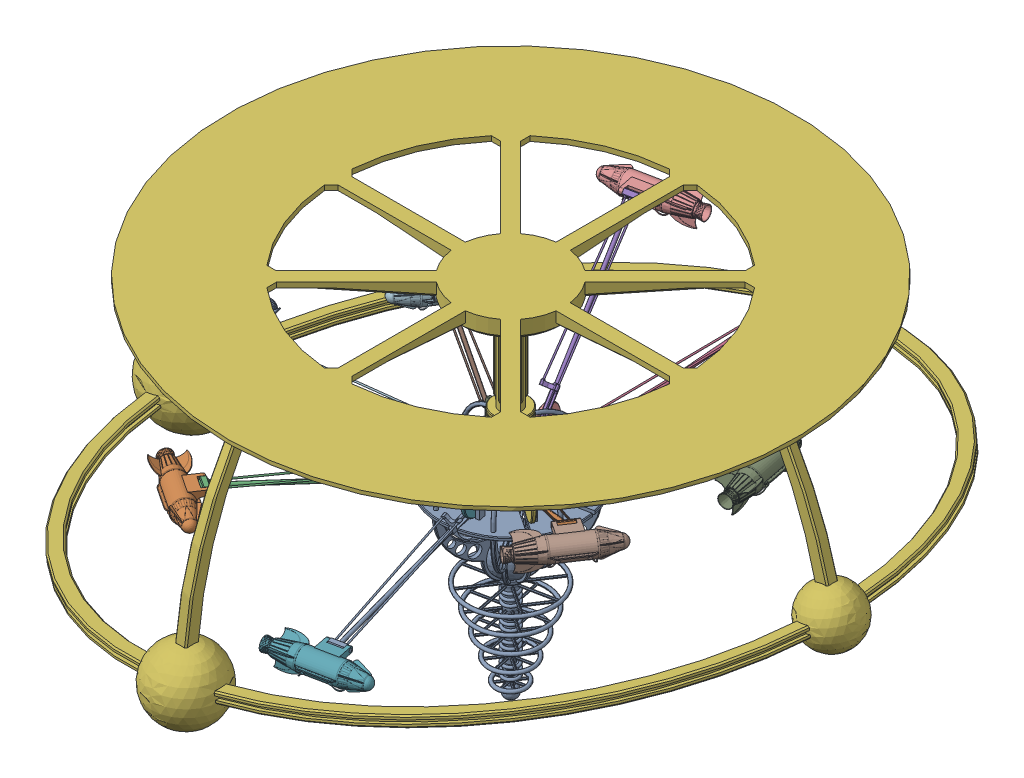
SolidWorks assembly Astro Orbiter Assembly, configuration Default. Lengths in mm.
Overall size (1005.89 517.61 1020).
26 component instances, 5 part files, 74 mates.
Components (placement in the parent):
- Astro Orbiter 1-1: Astro Orbiter 1 [Default] at (-37.4534 8.2623 -30.7627) x (-0.832861 0 -0.553482) z (0.553482 0 -0.832861) size (199.94 344.61 199.94)
- Astro Orbiter 2-1: Astro Orbiter 2 [Default] at (-69.9507 38.7623 31.6887) x (0.48296 0.488461 -0.726743) z (-0.832861 0 -0.553482) size (50 50 10)
- Astro Orbiter 3-1: Astro Orbiter 3 [Default] at (-76.7931 26.9845 23.9175) x (-0.550749 0.099257 0.828749) z (0.832861 0 0.553482) size (293 20 30)
- Astro Orbiter 2-2: Astro Orbiter 2 [Default] at (-4.9562 38.7623 -93.2141) x (-0.258225 -0.884497 0.388568) z (0.832861 0 0.553482) size (50 50 10)
- Astro Orbiter 2-3: Astro Orbiter 2 [Default] at (29.6854 38.7623 -51.9435) x (0.956571 0.218659 -0.192771) z (0.197551 0 0.980293) size (50 50 10)
- Astro Orbiter 2-4: Astro Orbiter 2 [Default] at (24.998 38.7623 1.7345) x (-0.624057 -0.662239 -0.41472) z (-0.553482 0 0.832861) size (50 50 10)
- Astro Orbiter 2-5: Astro Orbiter 2 [Default] at (-16.2727 38.7623 36.3761) x (0.064285 0.945574 0.318995) z (-0.980293 0 0.197551) size (50 50 10)
- Astro Orbiter 2-6: Astro Orbiter 2 [Default] at (-104.5923 38.7623 -9.5819) x (-0.782619 0.60219 0.157716) z (-0.197551 0 -0.980293) size (50 50 10)
- Astro Orbiter 2-7: Astro Orbiter 2 [Default] at (-99.9048 38.7623 -63.26) x (-0.518205 0.78286 -0.344375) z (0.553482 0 -0.832861) size (50 50 10)
- Astro Orbiter 2-8: Astro Orbiter 2 [Default] at (-58.6342 38.7623 -97.9016) x (-0.178151 -0.432156 -0.884027) z (0.980293 0 -0.197551) size (50 50 10)
- Astro Orbiter 3-2: Astro Orbiter 3 [Default] at (-92.2874 23.0484 -70.2045) x (-0.832848 -0.005705 -0.553473) z (-0.553482 0 0.832861) size (293 20 30)
- Astro Orbiter 3-3: Astro Orbiter 3 [Default] at (-103.7427 28.6003 -19.9542) x (-0.97031 0.142346 0.19554) z (0.197551 0 0.980293) size (293 20 30)
- Astro Orbiter 3-4: Astro Orbiter 3 [Default] at (-26.6076 19.4622 35.7117) x (0.196534 -0.101336 0.975246) z (0.980293 0 -0.197551) size (293 20 30)
- Astro Orbiter 3-5: Astro Orbiter 3 [Default] at (13.8271 40.6354 6.3177) x (0.738091 0.463282 0.490502) z (0.553482 0 -0.832861) size (293 20 30)
- Astro Orbiter 3-6: Astro Orbiter 3 [Default] at (24.7521 41.1619 -40.7483) x (0.861411 0.477322 -0.173594) z (-0.197551 0 -0.980293) size (293 20 30)
- Astro Orbiter 3-7: Astro Orbiter 3 [Default] at (-1.5461 44.1955 -80.2781) x (0.45922 0.558219 -0.69102) z (-0.832861 0 -0.553482) size (293 20 30)
- Astro Orbiter 3-8: Astro Orbiter 3 [Default] at (-45.9145 51.0011 -85.4032) x (-0.132939 0.7397 -0.659675) z (-0.980293 0 0.197551) size (293 20 30)
- Astro Orbiter 4-1: Astro Orbiter 4 [Default] at (-37.4534 3.2623 -30.7627) size (1005.89 407.25 1020)
- Astro Orbiter 5-1: Astro Orbiter 5 [Default] at (87.9556 -15.517 289.3084) x (-0.980293 0 0.197551) z (0.197551 0 0.980293) size (131 41.05 52.64)
- Astro Orbiter 5-2: Astro Orbiter 5 [Default] at (251.8514 144.8343 89.807) x (-0.553482 0 0.832861) z (0.832861 0 0.553482) size (131 41.05 52.64)
- Astro Orbiter 5-3: Astro Orbiter 5 [Default] at (250.2885 148.8217 -149.6567) x (0.197551 0 0.980293) z (0.980293 0 -0.197551) size (131 41.05 52.64)
- Astro Orbiter 5-4: Astro Orbiter 5 [Default] at (-144.8016 223.3372 -261.2115) x (0.980293 0 -0.197551) z (-0.197551 0 -0.980293) size (131 41.05 52.64)
- Astro Orbiter 5-5: Astro Orbiter 5 [Default] at (74.2323 171.7966 -306.6993) x (0.832861 0 0.553482) z (0.553482 0 -0.832861) size (131 41.05 52.64)
- Astro Orbiter 5-6: Astro Orbiter 5 [Default] at (-353.6693 11.6422 -169.2162) x (0.553482 0 -0.832861) z (-0.832861 0 -0.553482) size (131 41.05 52.64)
- Astro Orbiter 5-7: Astro Orbiter 5 [Default] at (-356.1227 53.6886 94.3639) x (-0.197551 0 -0.980293) z (-0.980293 0 0.197551) size (131 41.05 52.64)
- Astro Orbiter 5-8: Astro Orbiter 5 [Default] at (-175.1332 41.4513 284.2889) x (-0.832861 0 -0.553482) z (-0.553482 0 0.832861) size (131 41.05 52.64)
Mates (geometry in assembly coordinates):
- Coincident1: coincident anti-aligned: plane of Astro Orbiter 1-1 through (-67.1833 43.2623 27.5244) normal (-0.832861 0 -0.553482); plane of Astro Orbiter 2-1 through (-69.9507 38.7623 31.6887) normal (0.832861 0 0.553482)
- Concentric1: concentric anti-aligned: cylinder of Astro Orbiter 1-1 through (-74.115 38.7623 28.9213) axis (0.832861 0 0.553482) radius 2.5; circle of Astro Orbiter 2-1
- Concentric2: concentric anti-aligned: cylinder of Astro Orbiter 1-1 through (-47.8114 23.2623 -1.6258) axis (-0.832861 0 -0.553482) radius 2.5; cylinder of Astro Orbiter 3-1 through (-60.3043 23.2623 -9.928) axis (0.832861 0 0.553482) radius 2.5
- Coincident3: coincident anti-aligned: plane of Astro Orbiter 1-1 through (-39.5356 28.2623 -32.1464) normal (0.832861 0 0.553482); plane of Astro Orbiter 3-1 through (-76.7931 26.9845 23.9175) normal (-0.832861 0 -0.553482)
- Tangent1: tangent anti-aligned: cylinder of Astro Orbiter 2-1 through (-87.9385 28.9931 40.6887) axis (0.832861 0 0.553482) radius 2.5; plane of Astro Orbiter 3-1 through (-61.7849 21.7672 1.3336) normal (0.054937 0.995062 -0.082667)
- Concentric3: concentric aligned: cylinder of Astro Orbiter 1-1 through (-0.7919 38.7623 -90.4467) axis (-0.832861 0 -0.553482) radius 2.5; cylinder of Astro Orbiter 2-2 through (-0.7919 38.7623 -90.4467) axis (-0.832861 0 -0.553482) radius 2.5
- Coincident4: coincident anti-aligned: plane of Astro Orbiter 1-1 through (-7.7236 43.2623 -89.0498) normal (0.832861 0 0.553482); plane of Astro Orbiter 2-2 through (-4.9562 38.7623 -93.2141) normal (-0.832861 0 -0.553482)
- Concentric4: concentric aligned: cylinder of Astro Orbiter 1-1 through (30.6732 38.7623 -47.042) axis (-0.197551 0 -0.980293) radius 2.5; cylinder of Astro Orbiter 2-3 through (30.6732 38.7623 -47.042) axis (-0.197551 0 -0.980293) radius 2.5
- Coincident5: coincident anti-aligned: plane of Astro Orbiter 1-1 through (24.7839 43.2623 -50.9557) normal (0.197551 0 0.980293); plane of Astro Orbiter 2-3 through (29.6854 38.7623 -51.9435) normal (-0.197551 0 -0.980293)
- Concentric5: concentric aligned: cylinder of Astro Orbiter 1-1 through (22.2306 38.7623 5.8988) axis (0.553482 0 -0.832861) radius 2.5; cylinder of Astro Orbiter 2-4 through (22.2306 38.7623 5.8988) axis (0.553482 0 -0.832861) radius 2.5
- Coincident6: coincident anti-aligned: plane of Astro Orbiter 1-1 through (20.8337 43.2623 -1.0329) normal (-0.553482 0 0.832861); plane of Astro Orbiter 2-4 through (24.998 38.7623 1.7345) normal (0.553482 0 -0.832861)
- Concentric6: concentric aligned: cylinder of Astro Orbiter 1-1 through (-21.1741 38.7623 37.3639) axis (0.980293 0 -0.197551) radius 2.5; cylinder of Astro Orbiter 2-5 through (-21.1741 38.7623 37.3639) axis (0.980293 0 -0.197551) radius 2.5
- Coincident7: coincident anti-aligned: plane of Astro Orbiter 1-1 through (-17.2604 43.2623 31.4747) normal (-0.980293 0 0.197551); plane of Astro Orbiter 2-5 through (-16.2727 38.7623 36.3761) normal (0.980293 0 -0.197551)
- Concentric7: concentric aligned: cylinder of Astro Orbiter 1-1 through (-105.58 38.7623 -14.4834) axis (0.197551 0 0.980293) radius 2.5; cylinder of Astro Orbiter 2-6 through (-105.58 38.7623 -14.4834) axis (0.197551 0 0.980293) radius 2.5
- Coincident8: coincident anti-aligned: plane of Astro Orbiter 1-1 through (-99.6908 43.2623 -10.5697) normal (-0.197551 0 -0.980293); plane of Astro Orbiter 2-6 through (-104.5923 38.7623 -9.5819) normal (0.197551 0 0.980293)
- Concentric8: concentric aligned: cylinder of Astro Orbiter 1-1 through (-97.1374 38.7623 -67.4243) axis (-0.553482 0 0.832861) radius 2.5; cylinder of Astro Orbiter 2-7 through (-97.1374 38.7623 -67.4243) axis (-0.553482 0 0.832861) radius 2.5
- Coincident9: coincident anti-aligned: plane of Astro Orbiter 1-1 through (-95.7405 43.2623 -60.4926) normal (0.553482 0 -0.832861); plane of Astro Orbiter 2-7 through (-99.9048 38.7623 -63.26) normal (-0.553482 0 0.832861)
- Concentric9: concentric aligned: cylinder of Astro Orbiter 1-1 through (-53.7328 38.7623 -98.8893) axis (-0.980293 0 0.197551) radius 2.5; cylinder of Astro Orbiter 2-8 through (-53.7328 38.7623 -98.8893) axis (-0.980293 0 0.197551) radius 2.5
- Coincident10: coincident anti-aligned: plane of Astro Orbiter 1-1 through (-57.6465 43.2623 -93.0001) normal (0.980293 0 -0.197551); plane of Astro Orbiter 2-8 through (-58.6342 38.7623 -97.9016) normal (-0.980293 0 0.197551)
- Concentric12: concentric anti-aligned: cylinder of Astro Orbiter 1-1 through (-24.1747 23.2623 -2.8356) axis (-0.980293 0 0.197551) radius 2.5; cylinder of Astro Orbiter 3-4 through (-38.8791 23.2623 0.1277) axis (0.980293 0 -0.197551) radius 2.5
- Coincident13: coincident anti-aligned: plane of Astro Orbiter 1-1 through (-39.9042 28.2623 -30.2688) normal (0.980293 0 -0.197551); plane of Astro Orbiter 3-4 through (-26.6076 19.4622 35.7117) normal (-0.980293 0 0.197551)
- Tangent4: tangent anti-aligned: cylinder of Astro Orbiter 2-5 through (-27.3613 19.8508 31.9717) axis (0.980293 0 -0.197551) radius 2.5; plane of Astro Orbiter 3-4 through (-32.0623 19.7618 8.6441) normal (0.020019 0.994852 0.099338)
- Concentric13: concentric anti-aligned: cylinder of Astro Orbiter 1-1 through (-8.3165 23.2623 -20.4047) axis (-0.553482 0 0.832861) radius 2.5; cylinder of Astro Orbiter 3-5 through (-16.6187 23.2623 -7.9118) axis (0.553482 0 -0.832861) radius 2.5
- Coincident14: coincident anti-aligned: plane of Astro Orbiter 1-1 through (-38.8371 28.2623 -28.6806) normal (0.553482 0 -0.832861); plane of Astro Orbiter 3-5 through (13.8271 40.6354 6.3177) normal (-0.553482 0 0.832861)
- Tangent5: tangent anti-aligned: cylinder of Astro Orbiter 2-4 through (31.9443 52.0071 18.3576) axis (0.553482 0 -0.832861) radius 2.5; plane of Astro Orbiter 3-5 through (-5.5058 25.6796 -6.5301) normal (-0.385849 0.886211 -0.256418)
- Concentric14: concentric anti-aligned: cylinder of Astro Orbiter 1-1 through (-9.5263 23.2623 -44.0414) axis (0.197551 0 0.980293) radius 2.5; cylinder of Astro Orbiter 3-6 through (-6.563 23.2623 -29.3371) axis (-0.197551 0 -0.980293) radius 2.5
- Coincident15: coincident anti-aligned: plane of Astro Orbiter 1-1 through (-36.9596 28.2623 -28.312) normal (-0.197551 0 -0.980293); plane of Astro Orbiter 3-6 through (24.7521 41.1619 -40.7483) normal (0.197551 0 0.980293)
- Tangent6: tangent anti-aligned: cylinder of Astro Orbiter 2-3 through (12.5295 34.3891 -38.2852) axis (-0.197551 0 -0.980293) radius 2.5; plane of Astro Orbiter 3-6 through (2.2331 25.8387 -36.2102) normal (-0.467915 0.878729 0.094296)
- Concentric15: concentric anti-aligned: cylinder of Astro Orbiter 1-1 through (-27.0954 23.2623 -59.8997) axis (0.832861 0 0.553482) radius 2.5; cylinder of Astro Orbiter 3-7 through (-14.6025 23.2623 -51.5974) axis (-0.832861 0 -0.553482) radius 2.5
- Coincident16: coincident anti-aligned: plane of Astro Orbiter 1-1 through (-35.3713 28.2623 -29.379) normal (-0.832861 0 -0.553482); plane of Astro Orbiter 3-7 through (-1.5461 44.1955 -80.2781) normal (0.832861 0 0.553482)
- Tangent7: tangent anti-aligned: cylinder of Astro Orbiter 2-2 through (8.5369 56.4522 -95.4507) axis (-0.832861 0 -0.553482) radius 2.5; plane of Astro Orbiter 3-7 through (-13.4022 26.7703 -62.4373) normal (-0.308964 0.829693 0.464919)
- Concentric18: concentric anti-aligned: cylinder of Astro Orbiter 1-1 through (-37.4534 8.2623 -30.7627) axis (0 1 0) radius 15; cylinder of Astro Orbiter 4-1 through (-37.4534 258.2623 -30.7627) axis (0 -1 0) radius 15
- GearMate1: gear = 30 : 20 mm: cylinder of Astro Orbiter 2-5 through (-21.1741 38.7623 37.3639) axis (0.980293 0 -0.197551) radius 25; cylinder of Astro Orbiter 4-1 through (-37.4534 258.2623 -30.7627) axis (0 -1 0) radius 15
- GearMate2: gear = 30 : 20 mm: cylinder of Astro Orbiter 2-4 through (22.2306 38.7623 5.8988) axis (0.553482 0 -0.832861) radius 25; cylinder of Astro Orbiter 4-1 through (-37.4534 258.2623 -30.7627) axis (0 -1 0) radius 15
- GearMate3: gear = 30 : 20 mm: cylinder of Astro Orbiter 2-3 through (30.6732 38.7623 -47.042) axis (-0.197551 0 -0.980293) radius 25; cylinder of Astro Orbiter 4-1 through (-37.4534 258.2623 -30.7627) axis (0 -1 0) radius 15
- GearMate4: gear = 30 : 20 mm: cylinder of Astro Orbiter 2-2 through (-0.7919 38.7623 -90.4467) axis (-0.832861 0 -0.553482) radius 25; cylinder of Astro Orbiter 4-1 through (-37.4534 258.2623 -30.7627) axis (0 -1 0) radius 15
- GearMate5: gear = 30 : 20 mm: cylinder of Astro Orbiter 2-8 through (-53.7328 38.7623 -98.8893) axis (-0.980293 0 0.197551) radius 25; cylinder of Astro Orbiter 4-1 through (-37.4534 258.2623 -30.7627) axis (0 -1 0) radius 15
- GearMate6: gear = 30 : 20 mm: cylinder of Astro Orbiter 2-7 through (-97.1374 38.7623 -67.4243) axis (-0.553482 0 0.832861) radius 25; cylinder of Astro Orbiter 4-1 through (-37.4534 258.2623 -30.7627) axis (0 -1 0) radius 15
- GearMate7: gear = 30 : 20 mm: cylinder of Astro Orbiter 2-6 through (-105.58 38.7623 -14.4834) axis (0.197551 0 0.980293) radius 25; cylinder of Astro Orbiter 4-1 through (-37.4534 258.2623 -30.7627) axis (0 -1 0) radius 15
- GearMate8: gear = 30 : 20 mm: cylinder of Astro Orbiter 2-1 through (-74.115 38.7623 28.9213) axis (0.832861 0 0.553482) radius 25; cylinder of Astro Orbiter 4-1 through (-37.4534 258.2623 -30.7627) axis (0 -1 0) radius 15
- Coincident18: coincident anti-aligned: plane of Astro Orbiter 1-1 through (-37.4534 8.2623 -30.7627) normal (0 -1 0); plane of Astro Orbiter 4-1 through (-37.4534 8.2623 -30.7627) normal (0 1 0)
- Concentric19: concentric anti-aligned: cylinder of Astro Orbiter 1-1 through (-50.7322 23.2623 -58.6899) axis (0.980293 0 -0.197551) radius 2.5; cylinder of Astro Orbiter 3-8 through (-36.0278 23.2623 -61.6531) axis (-0.980293 0 0.197551) radius 2.5
- Coincident19: coincident anti-aligned: plane of Astro Orbiter 1-1 through (-35.0027 28.2623 -31.2566) normal (-0.980293 0 0.197551); plane of Astro Orbiter 3-8 through (-45.9145 51.0011 -85.4032) normal (0.980293 0 -0.197551)
- Tangent9: tangent anti-aligned: cylinder of Astro Orbiter 2-8 through (-45.2683 47.4054 -82.1965) axis (-0.980293 0 0.197551) radius 2.5; plane of Astro Orbiter 3-8 through (-41.8933 32.3417 -65.4493) normal (-0.146129 -0.672937 -0.725123)
- Concentric20: concentric anti-aligned: cylinder of Astro Orbiter 1-1 through (-66.5904 23.2623 -41.1207) axis (0.553482 0 -0.832861) radius 2.5; cylinder of Astro Orbiter 3-2 through (-58.2882 23.2623 -53.6136) axis (-0.553482 0 0.832861) radius 2.5
- Coincident20: coincident aligned: plane of Astro Orbiter 1-1 through (-33.3023 28.2623 -37.0092) normal (0.553482 0 -0.832861); plane of Astro Orbiter 3-2 through (-58.2882 23.2623 -53.6136) normal (0.553482 0 -0.832861)
- Tangent10: tangent anti-aligned: cylinder of Astro Orbiter 2-7 through (-84.0059 23.1051 -64.7011) axis (-0.553482 0 0.832861) radius 2.5; plane of Astro Orbiter 3-2 through (-69.3959 25.7052 -54.9919) normal (0.004751 -0.999984 0.003157)
- Concentric21: concentric anti-aligned: cylinder of Astro Orbiter 1-1 through (-65.3806 23.2623 -17.484) axis (-0.197551 0 -0.980293) radius 2.5; cylinder of Astro Orbiter 3-3 through (-68.3438 23.2623 -32.1884) axis (0.197551 0 0.980293) radius 2.5
- Coincident21: coincident aligned: plane of Astro Orbiter 1-1 through (-35.9718 28.2623 -23.4105) normal (0.197551 0 0.980293); plane of Astro Orbiter 3-3 through (-65.3806 23.2623 -17.484) normal (0.197551 0 0.980293)
- Tangent11: tangent anti-aligned: cylinder of Astro Orbiter 2-6 through (-90.9154 26.7185 -22.5392) axis (0.197551 0 0.980293) radius 2.5; plane of Astro Orbiter 3-3 through (-76.7103 27.1603 -25.4018) normal (-0.139541 -0.989817 0.028121)
- Parallel1: parallel aligned: plane of Astro Orbiter 4-1 through (-37.4534 258.2623 -30.7627) normal (0 -1 0); plane of Astro Orbiter 5-1 through (41.8819 -10.517 298.5933) normal (0 -1 0)
- Parallel2: parallel aligned: plane of Astro Orbiter 4-1 through (-37.4534 258.2623 -30.7627) normal (0 -1 0); plane of Astro Orbiter 5-2 through (225.8378 149.8343 128.9514) normal (0 -1 0)
- Concentric24: concentric anti-aligned: cylinder of Astro Orbiter 3-5 through (188.848 154.8343 137.6371) axis (0.553482 0 -0.832861) radius 2.5; cylinder of Astro Orbiter 5-2 through (205.4525 154.8343 112.6513) axis (-0.553482 0 0.832861) radius 2.5
- Coincident26: coincident aligned: plane of Astro Orbiter 3-5 through (188.848 154.8343 137.6371) normal (-0.553482 0 0.832861); plane of Astro Orbiter 5-2 through (185.5166 150.8343 135.4232) normal (-0.553482 0 0.832861)
- Concentric25: concentric anti-aligned: cylinder of Astro Orbiter 3-4 through (9.5844 -5.517 278.5793) axis (0.980293 0 -0.197551) radius 2.5; cylinder of Astro Orbiter 5-1 through (38.9932 -5.517 272.6527) axis (-0.980293 0 0.197551) radius 2.5
- Coincident27: coincident aligned: plane of Astro Orbiter 3-4 through (9.5844 -5.517 278.5793) normal (-0.980293 0 0.197551); plane of Astro Orbiter 5-1 through (8.7942 -9.517 274.6581) normal (-0.980293 0 0.197551)
- Concentric26: concentric anti-aligned: cylinder of Astro Orbiter 3-6 through (239.5593 158.8217 -71.2855) axis (-0.197551 0 -0.980293) radius 2.5; cylinder of Astro Orbiter 5-3 through (233.6328 158.8217 -100.6943) axis (0.197551 0 0.980293) radius 2.5
- Coincident28: coincident aligned: plane of Astro Orbiter 3-6 through (239.5593 158.8217 -71.2855) normal (0.197551 0 0.980293); plane of Astro Orbiter 5-3 through (235.6382 154.8217 -70.4953) normal (0.197551 0 0.980293)
- Parallel3: parallel aligned: plane of Astro Orbiter 4-1 through (-37.4534 258.2623 -30.7627) normal (0 -1 0); plane of Astro Orbiter 5-3 through (259.5734 153.8217 -103.583) normal (0 -1 0)
- Concentric27: concentric anti-aligned: cylinder of Astro Orbiter 3-8 through (-66.4304 233.3372 -250.4824) axis (-0.980293 0 0.197551) radius 2.5; cylinder of Astro Orbiter 5-4 through (-95.8392 233.3372 -244.5559) axis (0.980293 0 -0.197551) radius 2.5
- Coincident30: coincident aligned: plane of Astro Orbiter 3-8 through (-66.4304 233.3372 -250.4824) normal (0.980293 0 -0.197551); plane of Astro Orbiter 5-4 through (-65.6402 229.3372 -246.5612) normal (0.980293 0 -0.197551)
- Parallel4: parallel aligned: plane of Astro Orbiter 4-1 through (-37.4534 258.2623 -30.7627) normal (0 -1 0); plane of Astro Orbiter 5-4 through (-98.7278 228.3372 -270.4964) normal (0 -1 0)
- Concentric28: concentric anti-aligned: cylinder of Astro Orbiter 3-7 through (122.0625 181.7966 -243.6959) axis (-0.832861 0 -0.553482) radius 2.5; cylinder of Astro Orbiter 5-5 through (97.0766 181.7966 -260.3003) axis (0.832861 0 0.553482) radius 2.5
- Coincident32: coincident aligned: plane of Astro Orbiter 3-7 through (122.0625 181.7966 -243.6959) normal (0.832861 0 0.553482); plane of Astro Orbiter 5-5 through (119.8485 177.7966 -240.3645) normal (0.832861 0 0.553482)
- Parallel5: parallel aligned: plane of Astro Orbiter 4-1 through (-37.4534 258.2623 -30.7627) normal (0 -1 0); plane of Astro Orbiter 5-5 through (113.3768 176.7966 -280.6857) normal (0 -1 0)
- Concentric29: concentric anti-aligned: cylinder of Astro Orbiter 3-2 through (-290.6658 21.6422 -217.0463) axis (-0.553482 0 0.832861) radius 2.5; cylinder of Astro Orbiter 5-6 through (-307.2703 21.6422 -192.0605) axis (0.553482 0 -0.832861) radius 2.5
- Coincident34: coincident aligned: plane of Astro Orbiter 3-2 through (-290.6658 21.6422 -217.0463) normal (0.553482 0 -0.832861); plane of Astro Orbiter 5-6 through (-287.3344 17.6422 -214.8324) normal (0.553482 0 -0.832861)
- Parallel6: parallel aligned: plane of Astro Orbiter 4-1 through (-37.4534 258.2623 -30.7627) normal (0 -1 0); plane of Astro Orbiter 5-6 through (-327.6556 16.6422 -208.3607) normal (0 -1 0)
- Concentric30: concentric anti-aligned: cylinder of Astro Orbiter 3-3 through (-345.3936 63.6886 15.9927) axis (0.197551 0 0.980293) radius 2.5; cylinder of Astro Orbiter 5-7 through (-339.467 63.6886 45.4014) axis (-0.197551 0 -0.980293) radius 2.5
- Coincident36: coincident aligned: plane of Astro Orbiter 3-3 through (-345.3936 63.6886 15.9927) normal (-0.197551 0 -0.980293); plane of Astro Orbiter 5-7 through (-341.4724 59.6886 15.2025) normal (-0.197551 0 -0.980293)
- Parallel7: parallel aligned: plane of Astro Orbiter 4-1 through (-37.4534 258.2623 -30.7627) normal (0 -1 0); plane of Astro Orbiter 5-7 through (-365.4076 58.6886 48.2901) normal (0 -1 0)
- Concentric31: concentric anti-aligned: cylinder of Astro Orbiter 3-1 through (-222.9634 51.4513 221.2855) axis (0.832861 0 0.553482) radius 2.5; cylinder of Astro Orbiter 5-8 through (-197.9775 51.4513 237.8899) axis (-0.832861 0 -0.553482) radius 2.5
- Coincident38: coincident aligned: plane of Astro Orbiter 3-1 through (-222.9634 51.4513 221.2855) normal (-0.832861 0 -0.553482); plane of Astro Orbiter 5-8 through (-220.7495 47.4513 217.954) normal (-0.832861 0 -0.553482)
- Parallel8: parallel aligned: plane of Astro Orbiter 4-1 through (-37.4534 258.2623 -30.7627) normal (0 -1 0); plane of Astro Orbiter 5-8 through (-214.2777 46.4513 258.2753) normal (0 -1 0)
